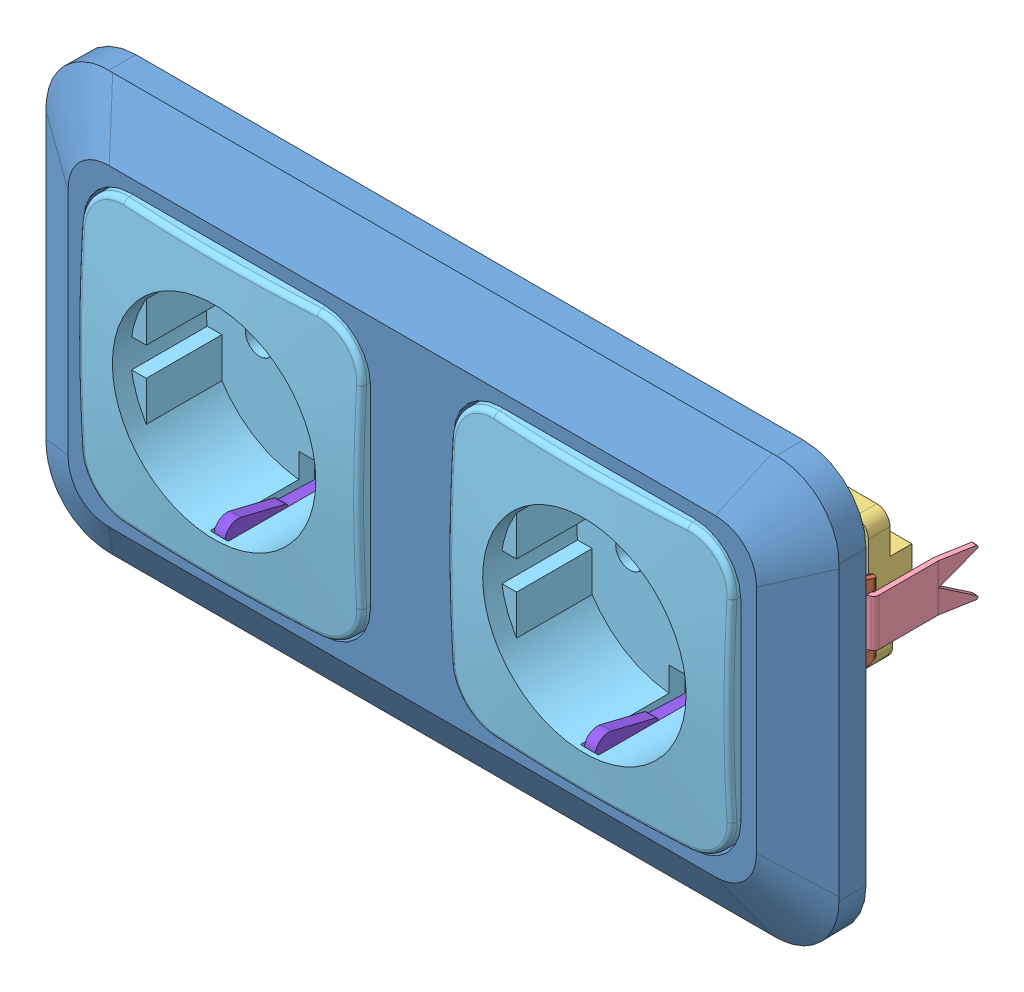
SolidWorks assembly Steckdose_2er, configuration Standard. Lengths in mm.
Overall size (152.53 80.54 49.07).
19 component instances, 8 part files, 6 mates.
Components (placement in the parent):
- Wandplatte_2er-1: Wandplatte_2er [Standard] at (52.6821 0 0) size (152.53 80.54 11)
- Steckdose-1: Steckdose [Standard] at (58.6803 50.9191 -11) x (1 0 0) z (0 -1 0) size (71 49.07 71)
  - Montageplatte.02-1: Montageplatte.02 [Standard] at (-76.9981 11 50.9191) x (1 0 0) z (0 1 0) size (71 71 18.97)
  - Halter-1: Halter [Standard] at (-76.9981 11 50.9191) x (1 0 0) z (0 1 0) size (45.97 31.9 15.37)
  - Kralle.04-1: Kralle.04 [Standard] at (-74.3121 12.4168 50.9191) x (0.996195 -0.087156 0) z (0.087156 0.996195 0) size (8.78 9 23.36)
  - Kralle.04-2: Kralle.04 [Standard] at (74.3121 12.4168 -50.9191) x (-0.996195 -0.087156 0) z (-0.087156 0.996195 0) size (8.78 9 23.36)
  - Buchse-1: Buchse [Standard] at (-76.9981 11 50.9191) x (1 0 0) z (0 1 0) size (64.03 64.03 27)
  - Stromklemme_1.02-1: Stromklemme_1.02 [Standard] at (-76.9981 11 50.7921) x (1 0 0) z (0 1 0) size (8.38 19.82 12.51)
  - Stromklemme_2.02-1: Stromklemme_2.02 [Standard] at (-76.9981 11 50.7921) x (1 0 0) z (0 1 0) size (8.38 19.82 12.51)
  - Erdleiter-1: Erdleiter [Standard] at (-76.9981 11 50.9191) x (1 0 0) z (0 1 0) size (7.24 44.01 27.12)
- Steckdose-2: Steckdose [Standard] at (129.6803 50.9191 -11) x (1 0 0) z (0 -1 0) size (71 49.07 71)
  - Montageplatte.02-1: Montageplatte.02 [Standard] at (-76.9981 11 50.9191) x (1 0 0) z (0 1 0) size (71 71 18.97)
  - Halter-1: Halter [Standard] at (-76.9981 11 50.9191) x (1 0 0) z (0 1 0) size (45.97 31.9 15.37)
  - Kralle.04-1: Kralle.04 [Standard] at (-74.3121 12.4168 50.9191) x (0.996195 -0.087156 0) z (0.087156 0.996195 0) size (8.78 9 23.36)
  - Kralle.04-2: Kralle.04 [Standard] at (74.3121 12.4168 -50.9191) x (-0.996195 -0.087156 0) z (-0.087156 0.996195 0) size (8.78 9 23.36)
  - Buchse-1: Buchse [Standard] at (-76.9981 11 50.9191) x (1 0 0) z (0 1 0) size (64.03 64.03 27)
  - Stromklemme_1.02-1: Stromklemme_1.02 [Standard] at (-76.9981 11 50.7921) x (1 0 0) z (0 1 0) size (8.38 19.82 12.51)
  - Stromklemme_2.02-1: Stromklemme_2.02 [Standard] at (-76.9981 11 50.7921) x (1 0 0) z (0 1 0) size (8.38 19.82 12.51)
  - Erdleiter-1: Erdleiter [Standard] at (-76.9981 11 50.9191) x (1 0 0) z (0 1 0) size (7.24 44.01 27.12)
Mates (geometry in assembly coordinates):
- Abstand1: distance = 0.5 mm anti-aligned: plane of Wandplatte_2er-1 through (31.1803 23.4191 0) normal (0 1 0); plane of Steckdose-1/Buchse-1 through (77.1803 23.9191 -6) normal (0 -1 0)
- Abstand4: distance = 0.5 mm anti-aligned: plane of Wandplatte_2er-1 through (102.1803 23.4191 0) normal (0 1 0); plane of Steckdose-2/Buchse-1 through (148.1803 23.9191 -6) normal (0 -1 0)
- Abstand2: distance = 0.5 mm anti-aligned: plane of Wandplatte_2er-1 through (31.1803 78.4191 0) normal (1 0 0); plane of Steckdose-1/Buchse-1 through (31.6803 32.4191 -6) normal (-1 0 0)
- Abstand3: distance = 0.5 mm anti-aligned: plane of Wandplatte_2er-1 through (102.1803 78.4191 0) normal (1 0 0); plane of Steckdose-2/Buchse-1 through (102.6803 32.4191 -6) normal (-1 0 0)
- Deckungsgleich5: coincident anti-aligned: plane of Wandplatte_2er-1 through (52.6821 0 -6) normal (0 0 1); plane of Steckdose-1/Buchse-1 through (58.6803 24.4191 -6) normal (0 0 -1)
- Deckungsgleich6: coincident anti-aligned: plane of Wandplatte_2er-1 through (52.6821 0 -6) normal (0 0 1); plane of Steckdose-2/Buchse-1 through (129.6803 24.4191 -6) normal (0 0 -1)
